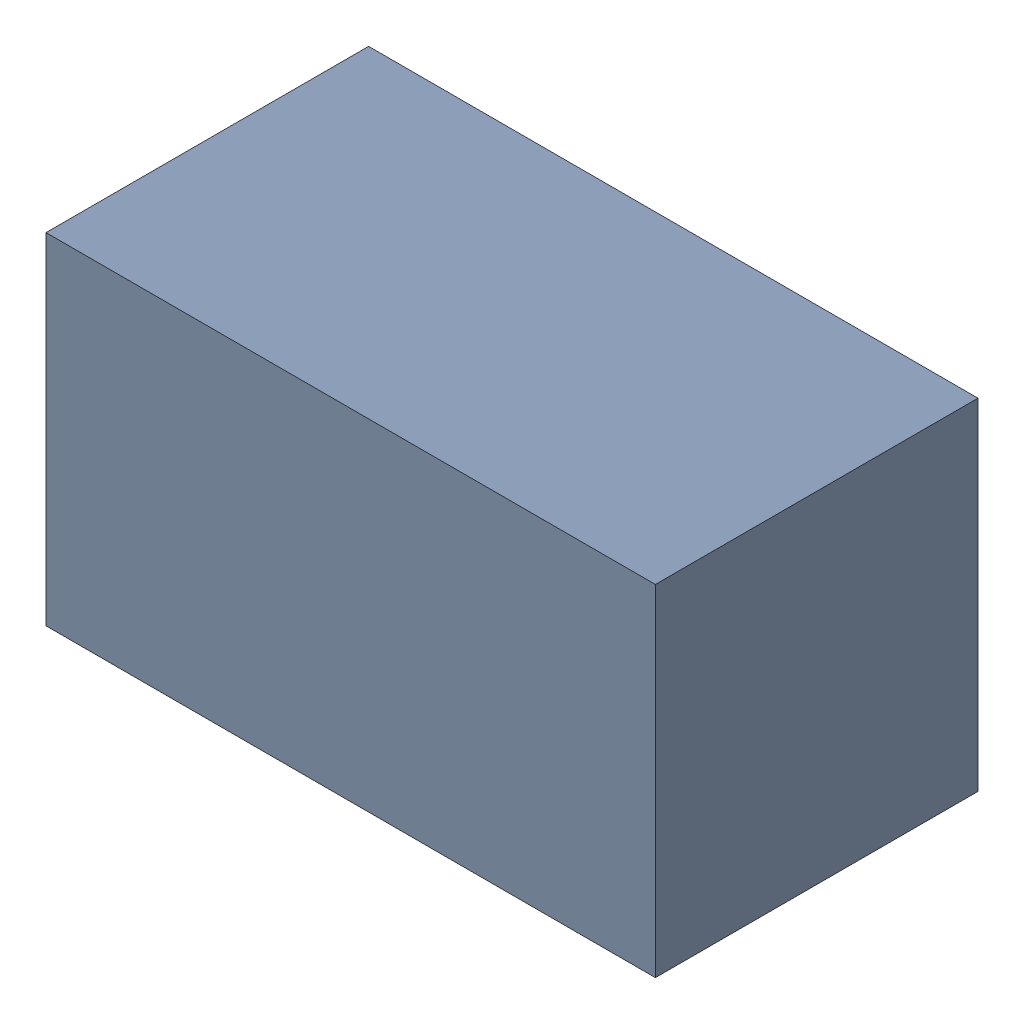
SolidWorks assembly R24, configuration Standard. Lengths in mm.
Overall size (1.7 0.95 0.9).
2 component instances, 1 part files, 0 mates.
Components (placement in the parent):
- 885541288-1: 885541288 [Standard] at (15.48 18.51 0) size (1.7 0.95 0.9)
  - Extruded_10-1: Extruded_10 [Standard] at origin size (1.7 0.95 0.9)
